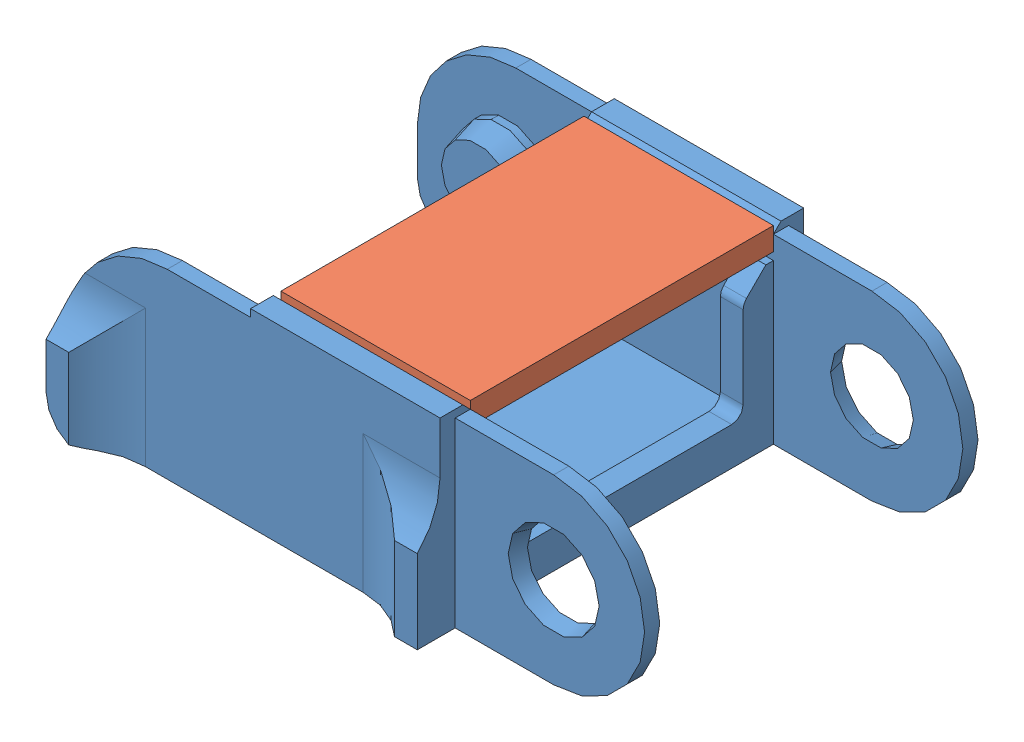
SolidWorks assembly chain_item, configuration Default. Lengths in mm.
Overall size (75 25 55.02).
2 component instances, 2 part files, 3 mates.
Components (placement in the parent):
- element-1: element [Default] at (59.0096 33.4872 25.705) size (75 25 55.02)
- chain spacer-1: chain spacer [Default] at (28.1505 72.5967 29.705) x (-1 0 0) z (0 0 1) size (25 6 44)
Mates (geometry in assembly coordinates):
- Coincident1: coincident aligned: plane of element-1 through (20.2301 57.2067 69.705) normal (0 1 0); plane of chain spacer-1 through (45.2301 57.2067 49.705) normal (0 1 0)
- Coincident2: coincident anti-aligned: plane of element-1 through (59.0096 33.4872 29.705) normal (0 0 1); plane of chain spacer-1 through (28.1505 72.5967 29.705) normal (0 0 -1)
- Coincident3: coincident aligned: plane of element-1 through (20.2301 57.2067 29.705) normal (-1 0 0); plane of chain spacer-1 through (20.2301 54.2067 49.705) normal (-1 0 0)
